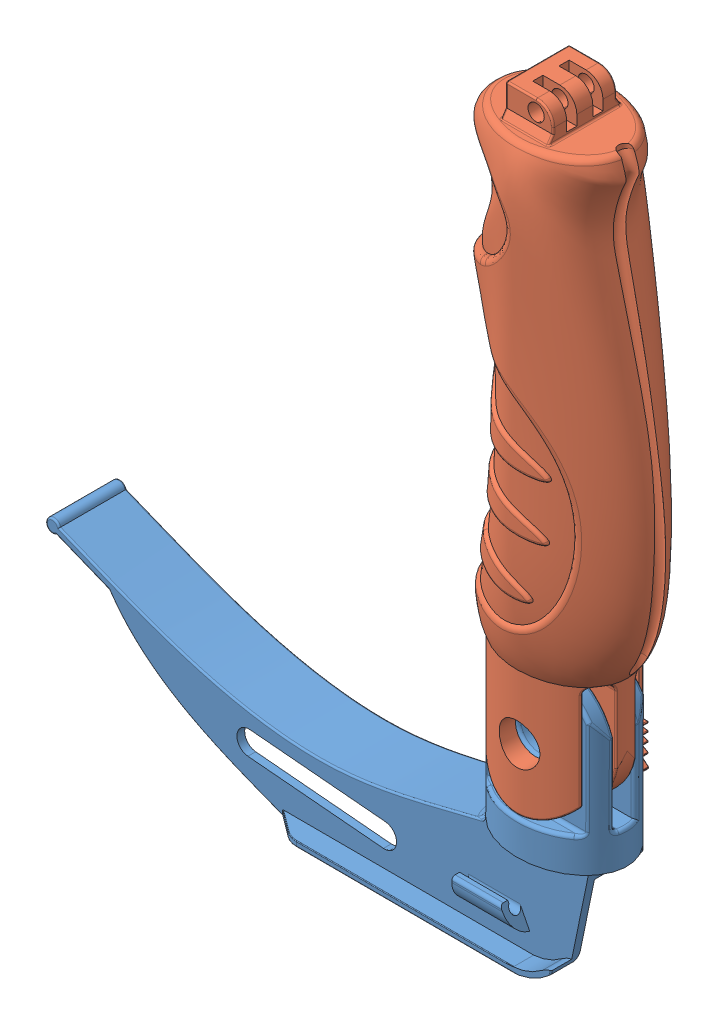
SolidWorks assembly Ensamblaje1, configuration Predeterminado. Lengths in mm.
Overall size (253.62 238.65 46.09).
2 component instances, 2 part files, 2 mates.
Components (placement in the parent):
- Laringo giro mod-2: Laringo giro mod [Predeterminado] at (-15.4826 -27.8348 164.4718) x (-0.999997 0.002439 0) z (0 0 -1) size (164.04 81.7 42.87)
- Modificacion giro-2: Modificacion giro [Predeterminado] at (-25.3387 50.1894 156.5173) size (213.41 193.6 38.12)
Mates (geometry in assembly coordinates):
- Concéntrica3: concentric aligned: cylinder of Laringo giro mod-2 through (-25.3387 31.1894 173.019) axis (0 0 -1) radius 5.75; circle of Modificacion giro-2
- Coincidente2: coincident anti-aligned: plane of Laringo giro mod-2 through (-6.8851 12.1443 159.4718) normal (0 0 -1); plane of Modificacion giro-2 through (4.1899 12.9803 159.4718) normal (0 0 1)
